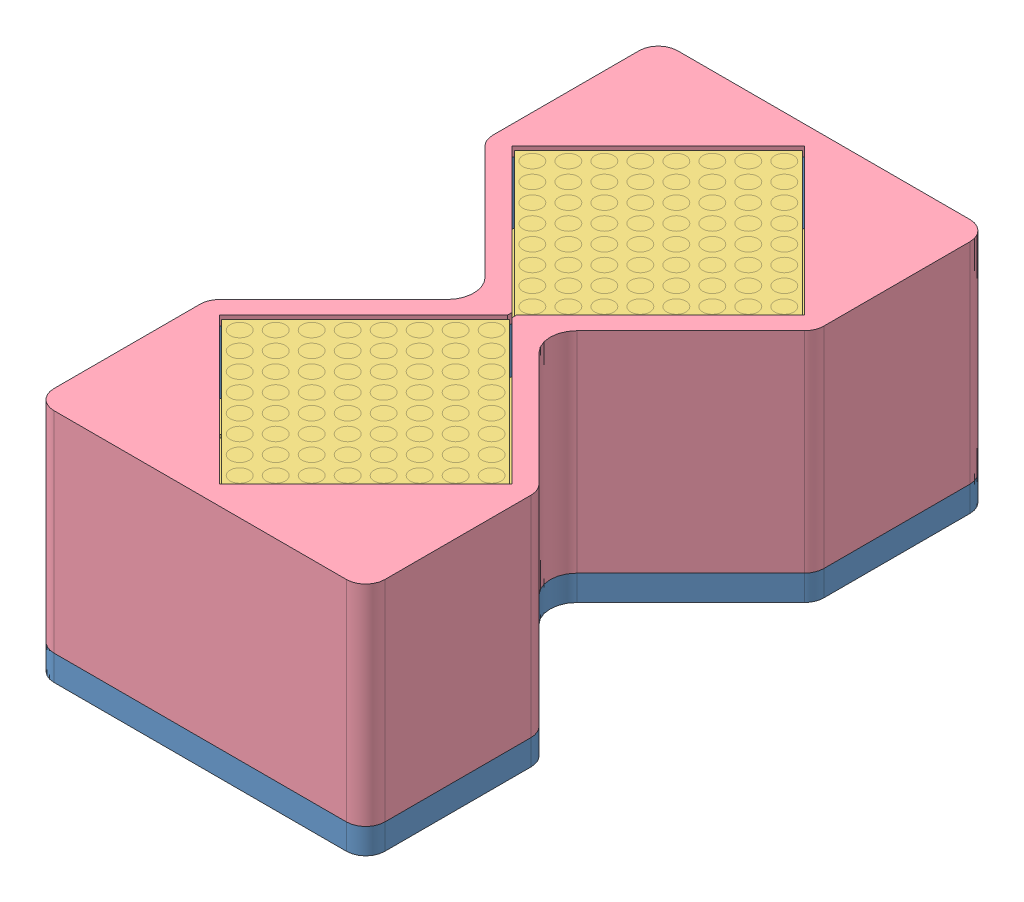
SolidWorks assembly 装配体, configuration 默认. Lengths in mm.
Overall size (52 40.64 98).
4 component instances, 4 part files, 6 mates.
Components (placement in the parent):
- 外壳-下-2: 外壳-下 [默认] at (13.8554 -113.908 60.8018) size (52 35.5 98)
- 船型开关-2: 船型开关 [默认] at (34.4895 -106.108 45.0018) x (1 0 0) z (0 -1 0) size (15 10.5 18.84)
- PCB-3: PCB [默认] at (13.8554 -92.2518 60.8018) x (1 0 0) z (0 1 0) size (47.03 92 32.64)
- 外壳-上-2: 外壳-上 [默认] at (13.8554 -82.408 -31.1982) x (1 0 0) z (0 0 -1) size (52 33 98)
Mates (geometry in assembly coordinates):
- 重合14: coincident anti-aligned: plane of 外壳-下-2 through (13.8554 -117.908 -31.1982) normal (0 -1 0); plane of 船型开关-2 through (37.3554 -117.908 45.0018) normal (0 1 0)
- 重合16: coincident anti-aligned: plane of 外壳-下-2 through (29.8554 -82.407 40.8018) normal (0 0 1); plane of 船型开关-2 through (37.3554 -117.908 40.8018) normal (0 0 -1)
- 重合18: coincident anti-aligned: plane of 外壳-下-2 through (29.8554 -82.407 49.8018) normal (1 0 0); plane of 船型开关-2 through (29.8554 -119.408 50.2518) normal (-1 0 0)
- 重合28: coincident anti-aligned: plane of 外壳-下-2 through (13.8554 -82.408 62.3018) normal (0 0 1); plane of 外壳-上-2 through (13.8554 -113.908 62.3018) normal (0 0 -1)
- 重合30: coincident anti-aligned: plane of 外壳-下-2 through (12.3554 -82.408 -31.1982) normal (-1 0 0); plane of 外壳-上-2 through (12.3554 -113.908 -8.1982) normal (1 0 0)
- 重合31: coincident anti-aligned: plane of 外壳-下-2 through (13.8554 -113.908 -31.1982) normal (0 1 0); plane of 外壳-上-2 through (13.8554 -113.908 37.8018) normal (0 -1 0)
